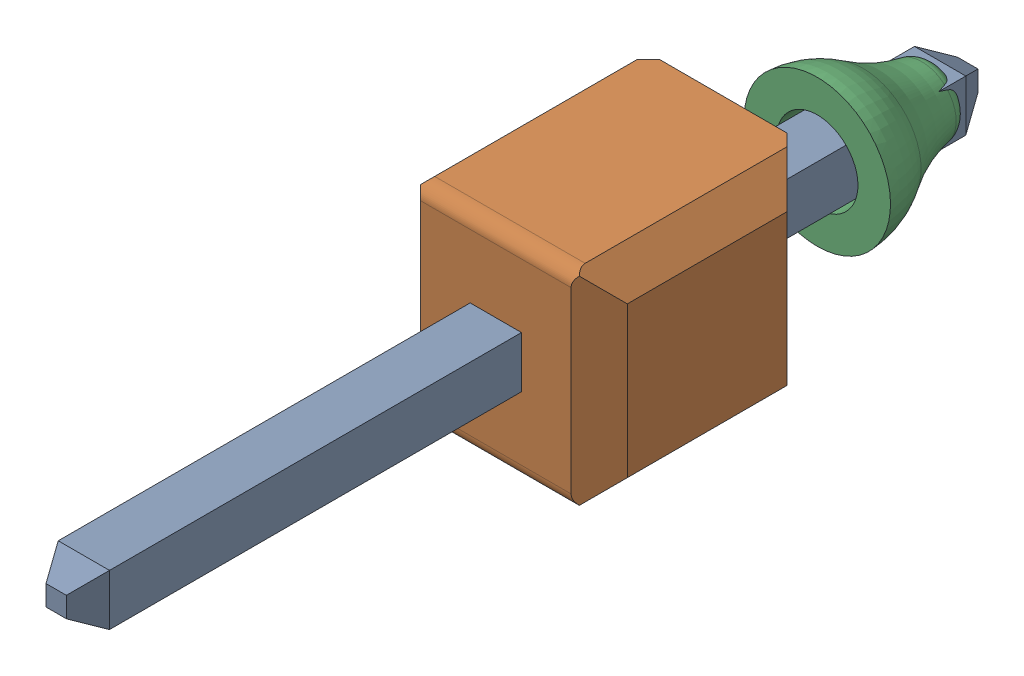
SolidWorks assembly DFPlayer Mini Pin, configuration Default. Lengths in mm.
Overall size (2.54 2.54 11.2).
3 component instances, 3 part files, 0 mates.
Components (placement in the parent):
- 11_20mm pin-1: 11_20mm pin [Default] at (0 0 2.6) size (0.63 0.63 11.2)
- Pin Header 1x12 TH Pitch 2-1: Pin Header 1x12 TH Pitch 2 [Default] at (-27.94 0 -0.0014) size (2.54 2.54 2.8)
- solder-1: solder [Default] at (0 0 -1.15) x (1 0 0) z (0 1 0) size (1.8 1.45 1.8)
